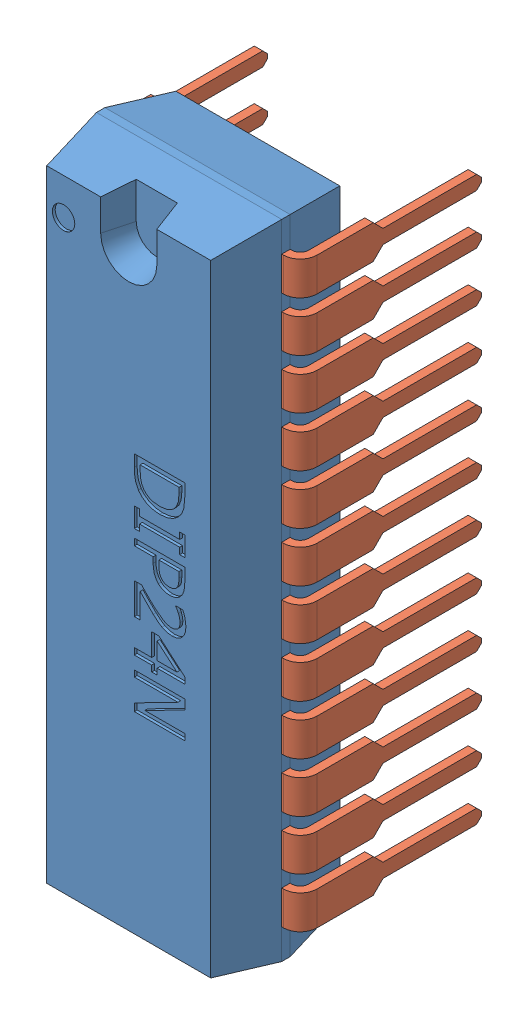
SolidWorks assembly DIP24, configuration Predeterminado. Lengths in mm.
Overall size (7.92 22.9 8.6).
26 component instances, 2 part files, 0 mates.
Components (placement in the parent):
- DIP24_1.stp-1: DIP24_1.stp [Predeterminado] at origin size (7.92 22.9 8.6)
  - DIP24_1_1.stp-1: DIP24_1_1.stp [Predeterminado] at (1.729 -1.7788 0.6) size (6.6 22.9 4.6)
  - DIP24_1_2.stp-1: DIP24_1_2.stp [Predeterminado] at (3.66 -9.2823 -1.5809) x (0 1 0) z (1 0 0) size (1.2 6.45 0.66)
  - DIP24_1_2.stp-2: DIP24_1_2.stp [Predeterminado] at (3.66 -7.5043 -1.5809) x (0 1 0) z (1 0 0) size (1.2 6.45 0.66)
  - DIP24_1_2.stp-3: DIP24_1_2.stp [Predeterminado] at (3.66 -5.7263 -1.5809) x (0 1 0) z (1 0 0) size (1.2 6.45 0.66)
  - DIP24_1_2.stp-4: DIP24_1_2.stp [Predeterminado] at (3.66 -3.9483 -1.5809) x (0 1 0) z (1 0 0) size (1.2 6.45 0.66)
  - DIP24_1_2.stp-5: DIP24_1_2.stp [Predeterminado] at (3.66 -2.1703 -1.5809) x (0 1 0) z (1 0 0) size (1.2 6.45 0.66)
  - DIP24_1_2.stp-6: DIP24_1_2.stp [Predeterminado] at (3.66 -0.3923 -1.5809) x (0 1 0) z (1 0 0) size (1.2 6.45 0.66)
  - DIP24_1_2.stp-7: DIP24_1_2.stp [Predeterminado] at (3.66 1.3857 -1.5809) x (0 1 0) z (1 0 0) size (1.2 6.45 0.66)
  - DIP24_1_2.stp-8: DIP24_1_2.stp [Predeterminado] at (3.66 3.1637 -1.5809) x (0 1 0) z (1 0 0) size (1.2 6.45 0.66)
  - DIP24_1_2.stp-9: DIP24_1_2.stp [Predeterminado] at (3.66 4.9417 -1.5809) x (0 1 0) z (1 0 0) size (1.2 6.45 0.66)
  - DIP24_1_2.stp-10: DIP24_1_2.stp [Predeterminado] at (3.66 6.7197 -1.5809) x (0 1 0) z (1 0 0) size (1.2 6.45 0.66)
  - DIP24_1_2.stp-11: DIP24_1_2.stp [Predeterminado] at (3.66 8.4977 -1.5809) x (0 1 0) z (1 0 0) size (1.2 6.45 0.66)
  - DIP24_1_2.stp-12: DIP24_1_2.stp [Predeterminado] at (3.66 10.2757 -1.5809) x (0 1 0) z (1 0 0) size (1.2 6.45 0.66)
  - DIP24_1_2.stp-13: DIP24_1_2.stp [Predeterminado] at (-3.66 -10.2757 -1.5809) x (0 -1 0) z (-1 0 0) size (1.2 6.45 0.66)
  - DIP24_1_2.stp-14: DIP24_1_2.stp [Predeterminado] at (-3.66 -8.4977 -1.5809) x (0 -1 0) z (-1 0 0) size (1.2 6.45 0.66)
  - DIP24_1_2.stp-15: DIP24_1_2.stp [Predeterminado] at (-3.66 -6.7197 -1.5809) x (0 -1 0) z (-1 0 0) size (1.2 6.45 0.66)
  - DIP24_1_2.stp-16: DIP24_1_2.stp [Predeterminado] at (-3.66 -4.9417 -1.5809) x (0 -1 0) z (-1 0 0) size (1.2 6.45 0.66)
  - DIP24_1_2.stp-17: DIP24_1_2.stp [Predeterminado] at (-3.66 -3.1637 -1.5809) x (0 -1 0) z (-1 0 0) size (1.2 6.45 0.66)
  - DIP24_1_2.stp-18: DIP24_1_2.stp [Predeterminado] at (-3.66 -1.3857 -1.5809) x (0 -1 0) z (-1 0 0) size (1.2 6.45 0.66)
  - DIP24_1_2.stp-19: DIP24_1_2.stp [Predeterminado] at (-3.66 0.3923 -1.5809) x (0 -1 0) z (-1 0 0) size (1.2 6.45 0.66)
  - DIP24_1_2.stp-20: DIP24_1_2.stp [Predeterminado] at (-3.66 2.1703 -1.5809) x (0 -1 0) z (-1 0 0) size (1.2 6.45 0.66)
  - DIP24_1_2.stp-21: DIP24_1_2.stp [Predeterminado] at (-3.66 3.9483 -1.5809) x (0 -1 0) z (-1 0 0) size (1.2 6.45 0.66)
  - DIP24_1_2.stp-22: DIP24_1_2.stp [Predeterminado] at (-3.66 5.7263 -1.5809) x (0 -1 0) z (-1 0 0) size (1.2 6.45 0.66)
  - DIP24_1_2.stp-23: DIP24_1_2.stp [Predeterminado] at (-3.66 7.5043 -1.5809) x (0 -1 0) z (-1 0 0) size (1.2 6.45 0.66)
  - DIP24_1_2.stp-24: DIP24_1_2.stp [Predeterminado] at (-3.66 9.2823 -1.5809) x (0 -1 0) z (-1 0 0) size (1.2 6.45 0.66)
